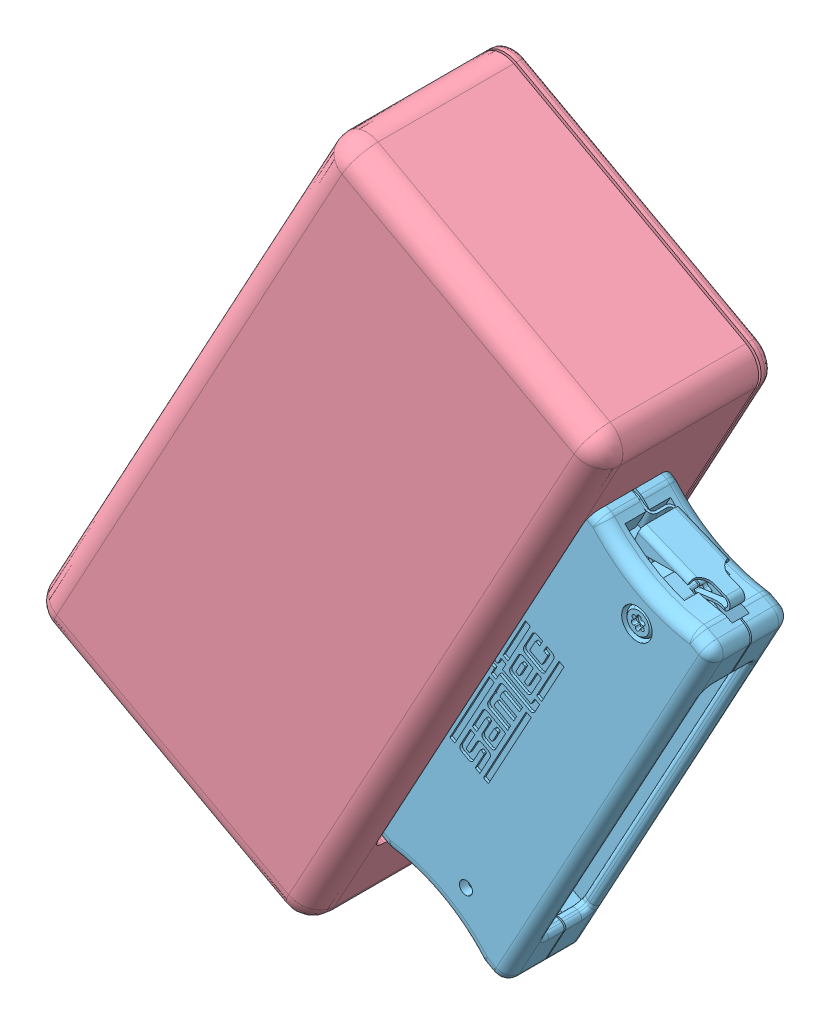
SolidWorks assembly easy connector fit assmebly, configuration Default. Lengths in mm.
Overall size (69.21 74.44 17.91).
9 component instances, 5 part files, 5 mates.
Components (placement in the parent):
- easy connector board asm-1: easy connector board asm [Default] at (42.8974 -27.0294 95.4089) x (0.477946 0.878389 0) z (-0.878389 0.477946 0) size (61.91 9.92 29.94)
  - easy connector board-1: easy connector board [Default] at (47.8394 20.0638 41.3103) size (61.91 1.63 29.94)
  - A79623-001-1: A79623-001 [Default] at (62.5587 21.6894 51.2163) size (4.45 2.05 6.53)
  - A79623-001-2: A79623-001 [Default] at (52.3987 21.6894 51.2163) size (4.45 2.05 6.53)
  - A79623-001-3: A79623-001 [Default] at (42.2387 21.6894 51.2163) size (4.45 2.05 6.53)
  - A79623-001-4: A79623-001 [Default] at (32.0787 21.6894 51.2163) size (4.45 2.05 6.53)
  - samtec female-1: samtec female [Default] at (48.2414 16.6138 40.3413) x (1 0 0) z (0 0 -1) size (45 8.59 11.36)
- easy connector box-1: easy connector box [Default] at (29.1383 34.9285 70.9735) x (-0.477946 -0.878389 0) z (0 0 1) size (67.06 32.51 17.91)
- ted connector-1: ted connector [Default] at (72.1124 11.9945 77.5848) x (-0.477946 -0.878389 0) z (-0.878389 0.477946 0) size (49.36 8.29 22.45)
Mates (geometry in assembly coordinates):
- Concentric1: concentric anti-aligned: cylinder of easy connector board asm-1/easy connector board-1 through (9.0022 16.2945 75.3451) axis (0 0 1) radius 1.4732; cylinder of easy connector box-1 through (9.0022 16.2945 73.7195) axis (0 0 -1) radius 2.032
- Concentric2: concentric anti-aligned: cylinder of easy connector board asm-1/easy connector board-1 through (50.3479 53.5392 75.3451) axis (0 0 1) radius 1.4732; cylinder of easy connector box-1 through (50.3479 53.5392 73.7195) axis (0 0 -1) radius 2.032
- Coincident1: coincident anti-aligned: plane of easy connector board asm-1/easy connector board-1 through (29.4756 34.7362 73.7195) normal (0 0 -1); plane of easy connector box-1 through (34.0831 62.3892 73.7195) normal (0 0 1)
- Width2: width aligned: plane of ted connector-1 through (31.6182 19.3136 77.2451) normal (-0.025272 0.013751 -0.999586); plane of ted connector-1 through (33.9071 18.0682 80.4201) normal (-0.025272 0.013751 0.999586); plane of easy connector board asm-1/samtec female-1 through (45.9181 46.9215 80.4751) normal (0 0 -1); plane of easy connector board asm-1/samtec female-1 through (45.4401 46.0431 77.1151) normal (0 0 1)
- Coincident3: coincident anti-aligned: plane of easy connector board asm-1/samtec female-1 through (29.7348 9.4378 75.3451) normal (0.878389 -0.477946 0); plane of ted connector-1 through (30.6907 11.1945 75.9951) normal (-0.878389 0.477946 0)
